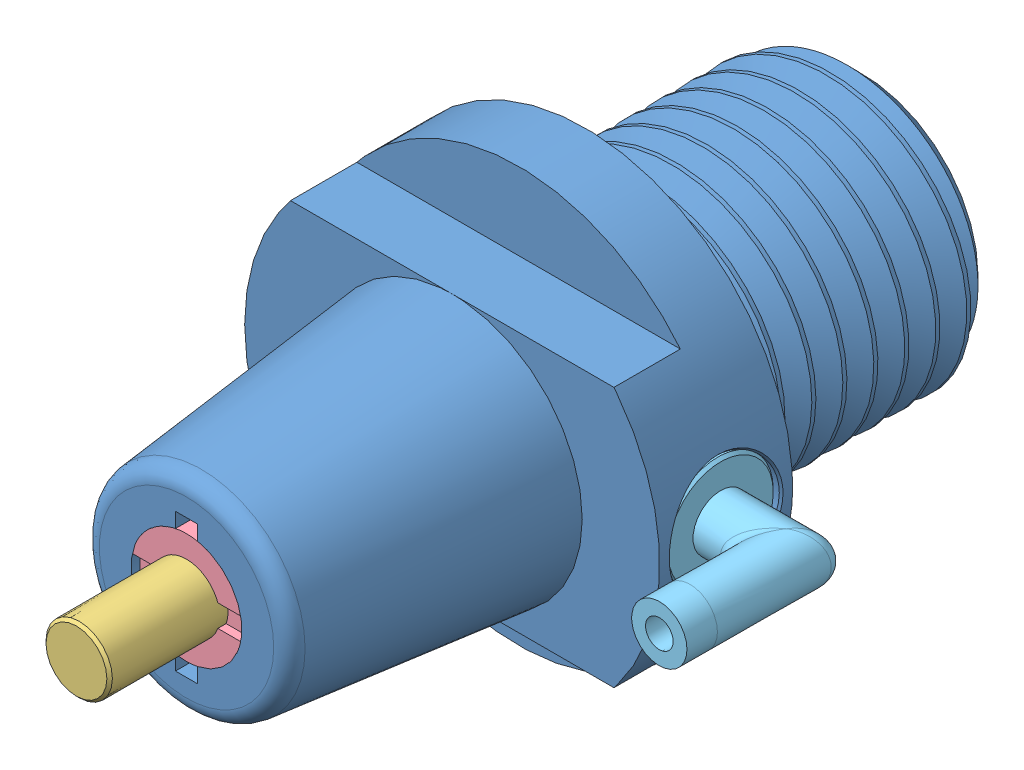
SolidWorks assembly Nippel and Plunger, configuration Default. Lengths in mm.
Overall size (9.13 7.5 14.43).
5 component instances, 5 part files, 6 mates.
Components (placement in the parent):
- CO2_Nippel_REAL-1: CO2_Nippel_REAL [Default] at (3.7547 10.0424 7.6011) size (7.5 7.5 12.44)
- Spring-1: Spring [Default] at (3.7547 10.0424 12.2046) x (0.998867 -0.047582 0) z (0 0 1) size (1.72 1.98 3.45)
- Plunger-6: Plunger [Default] at (3.7547 10.0424 21.7901) x (-1 0 0) z (0 0 -1) size (2 2.5 14.2)
- Lock-4: Lock [Default] at (3.7547 10.0424 19.2511) x (0 -1 0) z (0 0 1) size (2 2.5 0.55)
- Valve-1: Valve [Default] at (5.0051 10.0424 13.8011) x (0 0.006519 0.999979) z (1 0 0) size (3.31 2.12 4.24)
Mates (geometry in assembly coordinates):
- Coincident11: coincident: line of CO2_Nippel_REAL-1 through (3.9547 11.0222 19.0011) axis (0 0 -1); line of Plunger-6 through (3.9547 11.0222 18.9401) axis (0 0 -1)
- Concentric14: concentric: circle of CO2_Nippel_REAL-1; cylinder of Plunger-6 through (3.7547 10.0424 19.7901) axis (0 0 1) radius 0.6
- Concentric15: concentric: circle of Plunger-6; circle of Lock-4
- Coincident16: coincident: point of CO2_Nippel_REAL-1; point of Lock-4
- Concentric16: concentric: cylinder of CO2_Nippel_REAL-1 through (7.0051 10.0424 13.8011) axis (1 0 0) radius 1; cylinder of Valve-1 through (7.4051 10.0424 13.8011) axis (-1 0 0) radius 1
- Distance1: distance = 0 mm: plane of Valve-1 through (7.0051 10.0424 13.8011) normal (-1 0 0); plane of CO2_Nippel_REAL-1 through (7.0051 10.0424 13.8011) normal (1 0 0)
